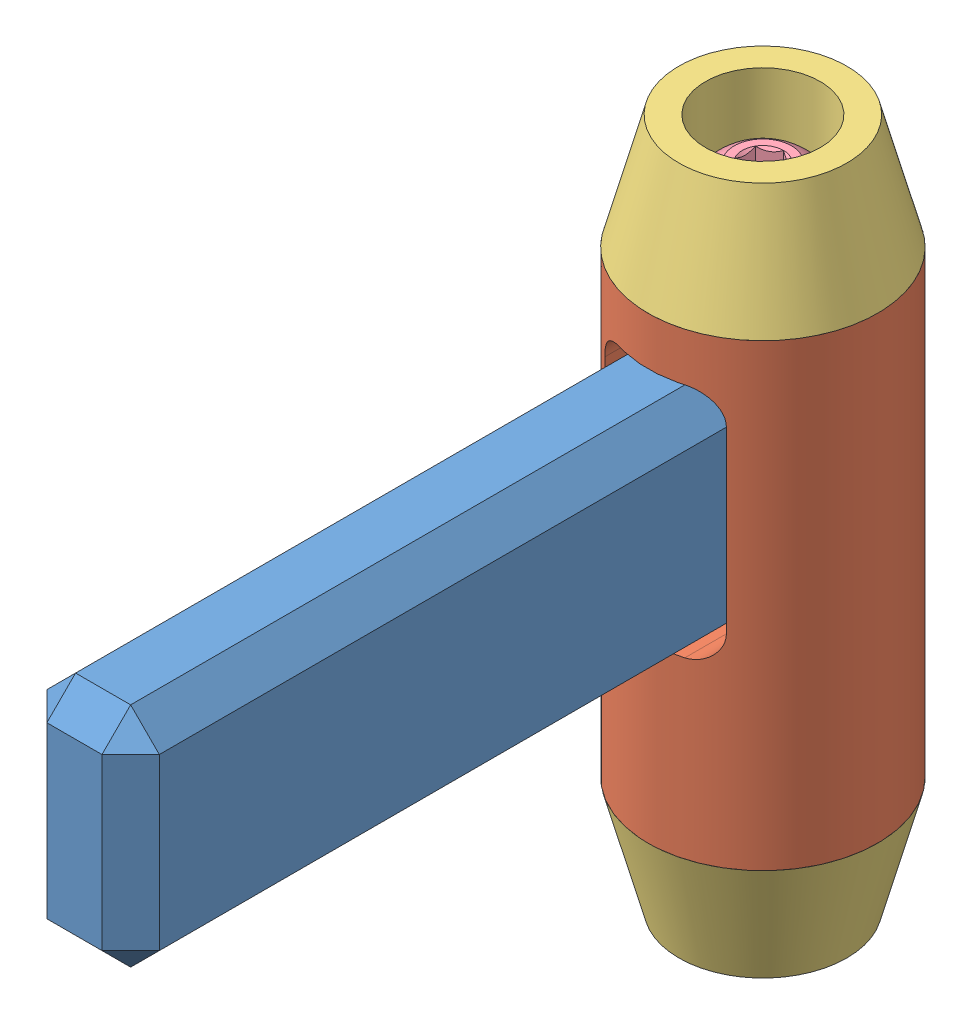
SolidWorks assembly Bump Stop Assembly (BS), configuration Default. Lengths in mm.
Overall size (14.59 38.1 45.39).
6 component instances, 4 part files, 9 mates.
Components (placement in the parent):
- Bump Stop Bar (BS-1)-1: Bump Stop Bar (BS-1) [Default] at (-30.3388 9.583 -9.5512) size (6.22 12.57 38.1)
- Bump Stop Rod (BS-2)-1: Bump Stop Rod (BS-2) [Default] at (-30.3388 18.7905 -9.5512) x (0 0 1) z (0 -1 0) size (12.7 12.7 25.4)
- Bump Stop Bumper (MMC 9540K842)-1: Bump Stop Bumper (MMC 9540K842) [Default] at (-30.3388 18.7905 -9.5512) x (0.986856 0 -0.161605) z (0 1 0) size (12.7 12.7 6.35)
- Bump Stop Bumper (MMC 9540K842)-2: Bump Stop Bumper (MMC 9540K842) [Default] at (-30.3388 -6.6095 -9.5512) x (1 0 0) z (0 -1 0) size (12.7 12.7 6.35)
- Bump Stop Bolt (MMC 91306A256)-1: Bump Stop Bolt (MMC 91306A256) [91306A256] at (-30.3388 22.8482 -9.5512) x (1 0 0) z (0 1 0) size (6.05 6.05 8.36)
- Bump Stop Bolt (MMC 91306A256)-2: Bump Stop Bolt (MMC 91306A256) [91306A256] at (-30.3388 -10.6671 -9.5512) x (1 0 0) z (0 -1 0) size (6.05 6.05 8.36)
Mates (geometry in assembly coordinates):
- Coincident1: coincident anti-aligned: plane of Bump Stop Bar (BS-1)-1 through (-30.3388 9.583 -9.5512) normal (0 0 -1); plane of Bump Stop Rod (BS-2)-1 through (-30.3388 18.7905 -9.5512) normal (0 0 1)
- Distance1: distance = 0.254 mm anti-aligned: plane of Bump Stop Bar (BS-1)-1 through (-33.4503 15.8695 28.5488) normal (0 1 0); plane of Bump Stop Rod (BS-2)-1 through (-26.9733 16.1235 -9.5512) normal (0 -1 0)
- Distance2: distance = 0.254 mm anti-aligned: plane of Bump Stop Bar (BS-1)-1 through (-27.2273 3.2965 28.5488) normal (1 0 0); plane of Bump Stop Rod (BS-2)-1 through (-26.9733 3.0425 -9.5512) normal (-1 0 0)
- Coincident2: coincident anti-aligned: circle of Bump Stop Rod (BS-2)-1; circle of Bump Stop Bumper (MMC 9540K842)-1
- Coincident3: coincident aligned: circle of Bump Stop Rod (BS-2)-1; circle of Bump Stop Bumper (MMC 9540K842)-2
- Coincident4: coincident anti-aligned: plane of Bump Stop Bumper (MMC 9540K842)-1 through (-30.3388 21.1718 -9.5512) normal (0 1 0); plane of Bump Stop Bolt (MMC 91306A256)-1 through (-30.3388 21.1718 -6.5286) normal (0 -1 0)
- Concentric3: concentric aligned: cylinder of Bump Stop Bumper (MMC 9540K842)-1 through (-30.3388 18.7905 -9.5512) axis (0 1 0) radius 1.5875; cylinder of Bump Stop Bolt (MMC 91306A256)-1 through (-30.3388 22.8482 -9.5512) axis (0 1 0) radius 3.0226
- Coincident5: coincident anti-aligned: plane of Bump Stop Bumper (MMC 9540K842)-2 through (-30.3388 -8.9907 -9.5512) normal (0 -1 0); plane of Bump Stop Bolt (MMC 91306A256)-2 through (-30.3388 -8.9907 -12.5738) normal (0 1 0)
- Concentric4: concentric aligned: cylinder of Bump Stop Bumper (MMC 9540K842)-2 through (-30.3388 -8.9907 -9.5512) axis (0 -1 0) radius 3.175; cylinder of Bump Stop Bolt (MMC 91306A256)-2 through (-30.3388 -10.6671 -9.5512) axis (0 -1 0) radius 3.0226
